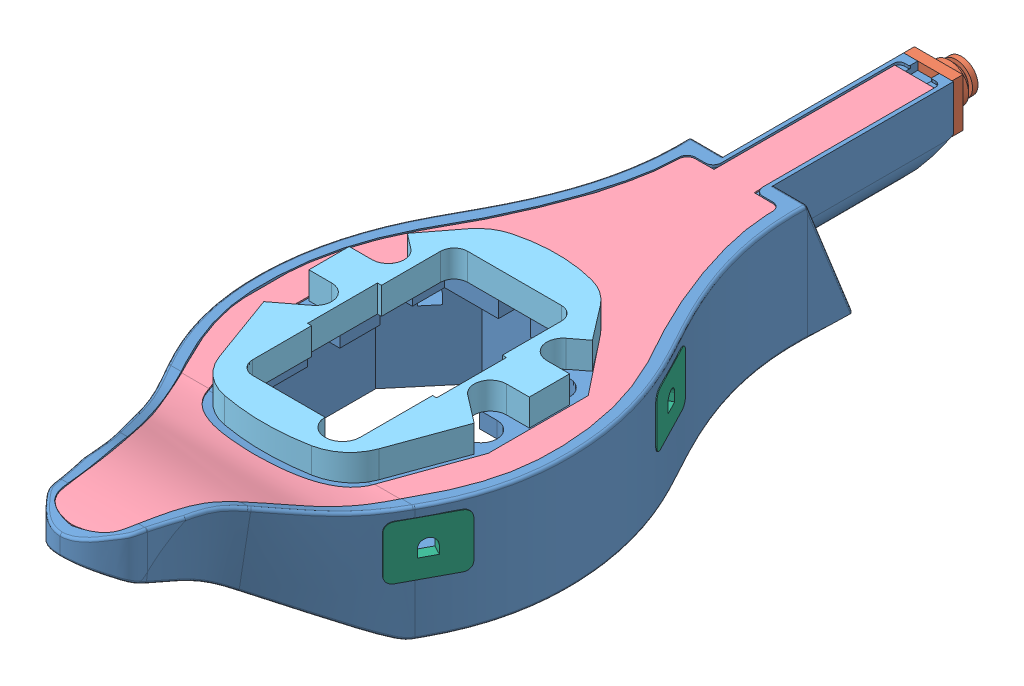
SolidWorks assembly structure, configuration Défaut. Lengths in mm.
Overall size (154.22 73.48 340.14).
9 component instances, 6 part files, 15 mates.
Components (placement in the parent):
- corps-2: corps [Défaut] at origin size (154.22 72.06 325.61)
- camera frontale-2: camera frontale [Défaut] at (-0.25 34 -67) x (-1 0 0) z (0 0 -1) size (18 18 12.52)
- aimant-2: aimant [Défaut] at (8 44.6997 195.4762) x (0 0.309017 0.951057) z (-1 0 0) size (7 1.7 16)
- blister de protection-1: blister de protection [Défaut] at (0.0011 -3 -0.036) x (1 0 0) z (0 1 0) size (107 322.51 31.6)
- mousse-1: mousse [Défaut] at (0 42 125) x (-1 0 0) z (0 0 -1) size (82 10 109)
- fixation-1: fixation [Défaut] at (45.287 29.3 74.0076) x (0.458572 0 0.888657) z (-0.888657 0 0.458572) size (25 20 4)
- fixation-2: fixation [Défaut] at (47.7844 29.3 166.8405) x (-0.47304 0 0.881041) z (-0.881041 0 -0.47304) size (25 20 4)
- fixation-3: fixation [Défaut] at (-45.2174 29.3 73.897) x (0.451803 0 -0.892118) z (0.892118 0 0.451803) size (25 20 4)
- fixation-4: fixation [Défaut] at (-47.8931 29.3 166.9012) x (-0.44985 0 -0.893104) z (0.893104 0 -0.44985) size (25 20 4)
Mates (geometry in assembly coordinates):
- Coïncidente1: coincident anti-aligned: plane of corps-2 through (8 43.6181 192.1475) normal (0 0.951057 -0.309017); plane of aimant-2 through (-8 43.6181 192.1475) normal (0 -0.951057 0.309017)
- Coïncidente2: coincident anti-aligned: plane of corps-2 through (8 45.7812 198.8049) normal (0 -0.309017 -0.951057); plane of aimant-2 through (-8 45.7812 198.8049) normal (0 0.309017 0.951057)
- Coïncidente3: coincident anti-aligned: plane of corps-2 through (-8 45.7812 198.8049) normal (1 0 0); plane of aimant-2 through (-8 45.2349 191.6222) normal (-1 0 0)
- Coïncidente4: coincident anti-aligned: plane of corps-2 through (-46.3882 42 87.9262) normal (0 1 0); plane of blister de protection-1 through (53.5011 42 169.8592) normal (0 -1 0)
- Distance1: distance = 0.275 mm anti-aligned: plane of blister de protection-1 through (7.475 104 -66.4284) normal (1 0 0); plane of corps-2 through (7.75 42 2.3697) normal (-1 0 0)
- Coïncidente6: coincident anti-aligned: plane of corps-2 through (0 25.25 -67) normal (0 0 -1); plane of camera frontale-2 through (8.75 25 -67) normal (0 0 1)
- Coïncidente8: coincident aligned: plane of corps-2 through (49.6499 43 83.7504) normal (0 1 0); plane of camera frontale-2 through (8.75 43 -71) normal (0 1 0)
- Coïncidente9: coincident aligned: plane of corps-2 through (-9.25 43 -67) normal (-1 0 0); plane of camera frontale-2 through (-9.25 43 -71) normal (-1 0 0)
- Coïncidente11: coincident anti-aligned: plane of corps-2 through (-46.3882 42 87.9262) normal (0 1 0); plane of mousse-1 through (10.2831 42 90.5666) normal (0 -1 0)
- Distance3: distance = 3.5 mm aligned: plane of mousse-1 through (22.5 52 167) normal (-1 0 0); plane of corps-2 through (26 -87.8467 138) normal (-1 0 0)
- Coïncidente14: coincident aligned: plane of corps-2 through (26 -87.8467 87) normal (0 0 1); plane of mousse-1 through (17.5 52 87) normal (0 0 1)
- Coïncidente15: coincident anti-aligned: plane of corps-2 through (-50.6996 26 63.1335) normal (0 1 0); plane of fixation-2 through (45.8213 26 162.0409) normal (0 -1 0)
- Coïncidente16: coincident anti-aligned: plane of corps-2 through (-50.6996 26 173.8665) normal (0 1 0); plane of fixation-1 through (40.2191 26 72.9093) normal (0 -1 0)
- Coïncidente17: coincident anti-aligned: plane of corps-2 through (-50.6996 26 173.8665) normal (0 1 0); plane of fixation-4 through (-42.8362 26 168.0491) normal (0 -1 0)
- Coïncidente18: coincident anti-aligned: plane of corps-2 through (-50.6996 26 63.1335) normal (0 1 0); plane of fixation-3 through (-43.1399 26 78.6482) normal (0 -1 0)
